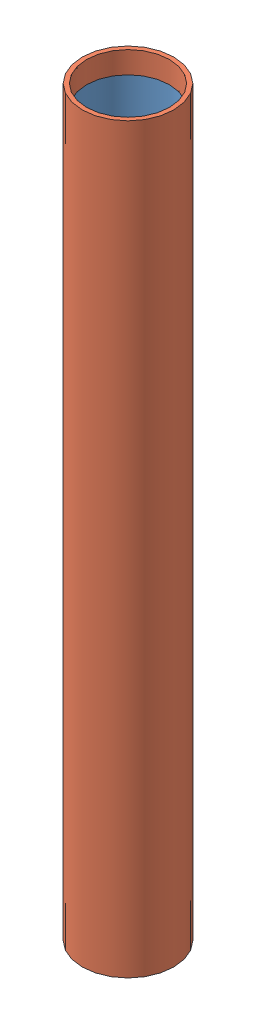
SolidWorks assembly Siebeinsatz, configuration Siebeinsatz 20". Lengths in mm.
Overall size (63 510 63).
2 component instances, 2 part files, 8 mates.
Components (placement in the parent):
- Filterstützrohr R4-15^Siebeinsatz-1: Filterstützrohr R4-15^Siebeinsatz [Filterstützrohr 20" D62-D58 x 510 - PP weiß] x (1 0 0) z (0 1 0) size (62 62 509) (virtual)
- Siebschlauch^Siebeinsatz-1: Siebschlauch^Siebeinsatz [Siebschlauch 25µm - PP grau] x (0 0 -1) z (1 0 0) size (63 510 63) (virtual)
Mates (geometry in assembly coordinates):
- Platziert1: in place: plane of Filterstützrohr R4-15^Siebeinsatz-1 through (0 0 0) normal (0 1 0); moOrthogonalPlaneRef_w of Filterstützrohr R4-15^Siebeinsatz-1 through (0 0 0) normal (0 0 -1); plane of Filterstützrohr R4-15^Siebeinsatz-1 through (0 0 0) normal (1 0 0); unknown of Filterstützrohr R4-15^Siebeinsatz-1
- Deckungsgleich1: coincident: plane of Filterstützrohr R4-15^Siebeinsatz-1; plane of assembly
- Deckungsgleich2: coincident: plane of Filterstützrohr R4-15^Siebeinsatz-1 through (0 0 0) normal (0 0 -1); moOrthogonalPlaneRef_w of assembly
- Deckungsgleich3: coincident: plane of Filterstützrohr R4-15^Siebeinsatz-1 through (0 0 0) normal (1 0 0); moOrthogonalPlaneRef_w of assembly
- Platziert2: in place: plane of Siebschlauch^Siebeinsatz-1 through (0 0 0) normal (1 0 0); plane of Siebschlauch^Siebeinsatz-1 through (0 0 0) normal (0 1 0); plane of Siebschlauch^Siebeinsatz-1 through (0 0 0) normal (0 0 -1); unknown of Siebschlauch^Siebeinsatz-1
- Deckungsgleich1: coincident: plane of Siebschlauch^Siebeinsatz-1; plane of assembly
- Deckungsgleich2: coincident: plane of Siebschlauch^Siebeinsatz-1 through (0 0 0) normal (0 1 0); moOrthogonalPlaneRef_w of assembly
- Deckungsgleich3: coincident: plane of Siebschlauch^Siebeinsatz-1 through (0 0 0) normal (0 0 -1); moOrthogonalPlaneRef_w of assembly
